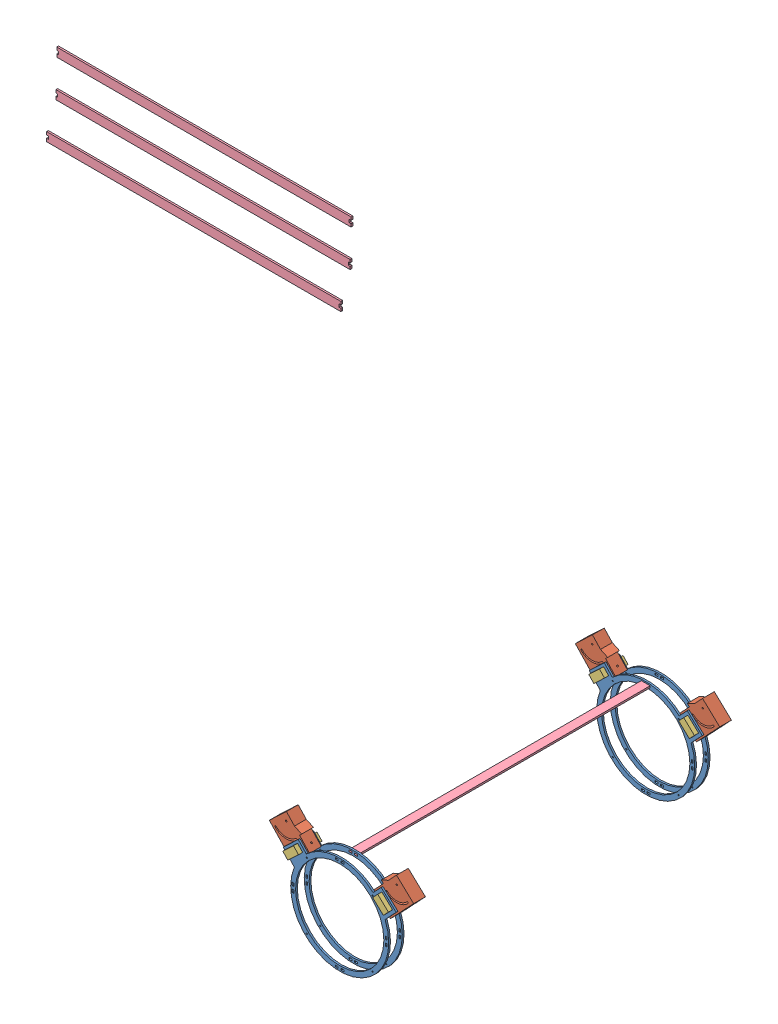
SolidWorks assembly Ensamblaje1, configuration Predeterminado. Lengths in mm.
Overall size (2307.62 1167.62 1120.02).
18 component instances, 4 part files, 7 mates.
Components (placement in the parent):
- Aramado-1: Aramado [Predeterminado] at (-348.9554 21.8342 490.6527) size (490.65 380.63 80.02)
  - Anillo acrilico-1: Anillo acrilico [Predeterminado] at (-159.8874 164.786 383.9345) size (383.93 333.2 6)
  - anclaje para base_1-3: anclaje para base_1 [Predeterminado] at (-195.9783 155.136 343.9345) x (0 0 -1) z (-0.685795 0.727795 0) size (40 90 115)
  - Anillo acrilico-2: Anillo acrilico [Predeterminado] at (-159.8874 164.786 337.9345) size (383.93 333.2 6)
  - anclaje para base_1-4: anclaje para base_1 [Predeterminado] at (184.5852 155.136 383.9345) x (0 0 1) z (0.685795 0.727795 0) size (40 90 115)
  - Pieza prisionera-1: Pieza prisionera [Predeterminado] at (-166.2782 137.2738 323.9284) x (-0.685795 0.727795 0) z (0 0 1) size (25 50 80)
  - Pieza prisionera-2: Pieza prisionera [Predeterminado] at (165.5199 127.2527 323.9108) x (0.685795 0.727795 0) z (0 0 1) size (25 50 80)
- Aramado-2: Aramado [Predeterminado] at (-348.9554 21.8342 1530.6527) size (490.65 380.63 80.02)
  - Anillo acrilico-1: Anillo acrilico [Predeterminado] at (-159.8874 164.786 383.9345) size (383.93 333.2 6)
  - anclaje para base_1-3: anclaje para base_1 [Predeterminado] at (-195.9783 155.136 343.9345) x (0 0 -1) z (-0.685795 0.727795 0) size (40 90 115)
  - Anillo acrilico-2: Anillo acrilico [Predeterminado] at (-159.8874 164.786 337.9345) size (383.93 333.2 6)
  - anclaje para base_1-4: anclaje para base_1 [Predeterminado] at (184.5852 155.136 383.9345) x (0 0 1) z (0.685795 0.727795 0) size (40 90 115)
  - Pieza prisionera-1: Pieza prisionera [Predeterminado] at (-166.2782 137.2738 323.9284) x (-0.685795 0.727795 0) z (0 0 1) size (25 50 80)
  - Pieza prisionera-2: Pieza prisionera [Predeterminado] at (165.5199 127.2527 323.9108) x (0.685795 0.727795 0) z (0 0 1) size (25 50 80)
- Barra anillo acrilico-1: Barra anillo acrilico [Predeterminado] at (-346.1008 189.0491 945.792) x (0 0 1) z (0 -1 0) size (1000 30 6)
- Barra anillo acrilico-2: Barra anillo acrilico [Predeterminado] at (-2345.737 745.1399 848.6022) size (1000 30 6)
- Barra anillo acrilico-3: Barra anillo acrilico [Predeterminado] at (-2317.0382 881.4591 845.6022) size (1000 30 6)
- Barra anillo acrilico-4: Barra anillo acrilico [Predeterminado] at (-2317.0382 1005.2226 842.6022) size (1000 30 6)
Mates (geometry in assembly coordinates):
- Coincidente2: coincident anti-aligned: plane of Aramado-2/Anillo acrilico-2 through (-1339.0562 189.0491 1864.5873) normal (0 -1 0); plane of Barra anillo acrilico-1 through (-1176.3143 189.0491 945.792) normal (0 1 0)
- Coincidente3: coincident anti-aligned: plane of Aramado-2/Anillo acrilico-2 through (-1169.8654 186.6202 1864.5873) normal (-1 0 0); plane of Barra anillo acrilico-1 through (-1169.8654 183.0491 945.792) normal (1 0 0)
- Coincidente5: coincident anti-aligned: line of Aramado-2/Anillo acrilico-2 through (-1179.8654 183.0491 1874.5873) axis (1 0 0); line of Barra anillo acrilico-1 through (-1169.8654 183.0491 1874.5873) axis (-1 0 0)
- Coincidente6: coincident aligned: line of Aramado-1/Anillo acrilico-1 through (-349.6519 183.0491 874.5873) axis (1 0 0); line of Barra anillo acrilico-1 through (-349.6519 183.0491 874.5873) axis (1 0 0)
- Coincidente7: coincident aligned: plane of Aramado-1/Anillo acrilico-1 through (-508.8427 186.6202 874.5873) normal (0 0 -1); plane of Barra anillo acrilico-1 through (-346.1008 183.0491 874.5873) normal (0 0 -1)
- Coincidente8: coincident anti-aligned: plane of Aramado-1/Anillo acrilico-1 through (-508.8427 183.0491 870.5873) normal (0 1 0); plane of Barra anillo acrilico-1 through (-346.1008 183.0491 945.792) normal (0 -1 0)
- Coincidente9: coincident anti-aligned: plane of Aramado-1/Anillo acrilico-1 through (-339.6519 186.6202 870.5873) normal (-1 0 0); plane of Barra anillo acrilico-1 through (-339.6519 183.0491 945.792) normal (1 0 0)
